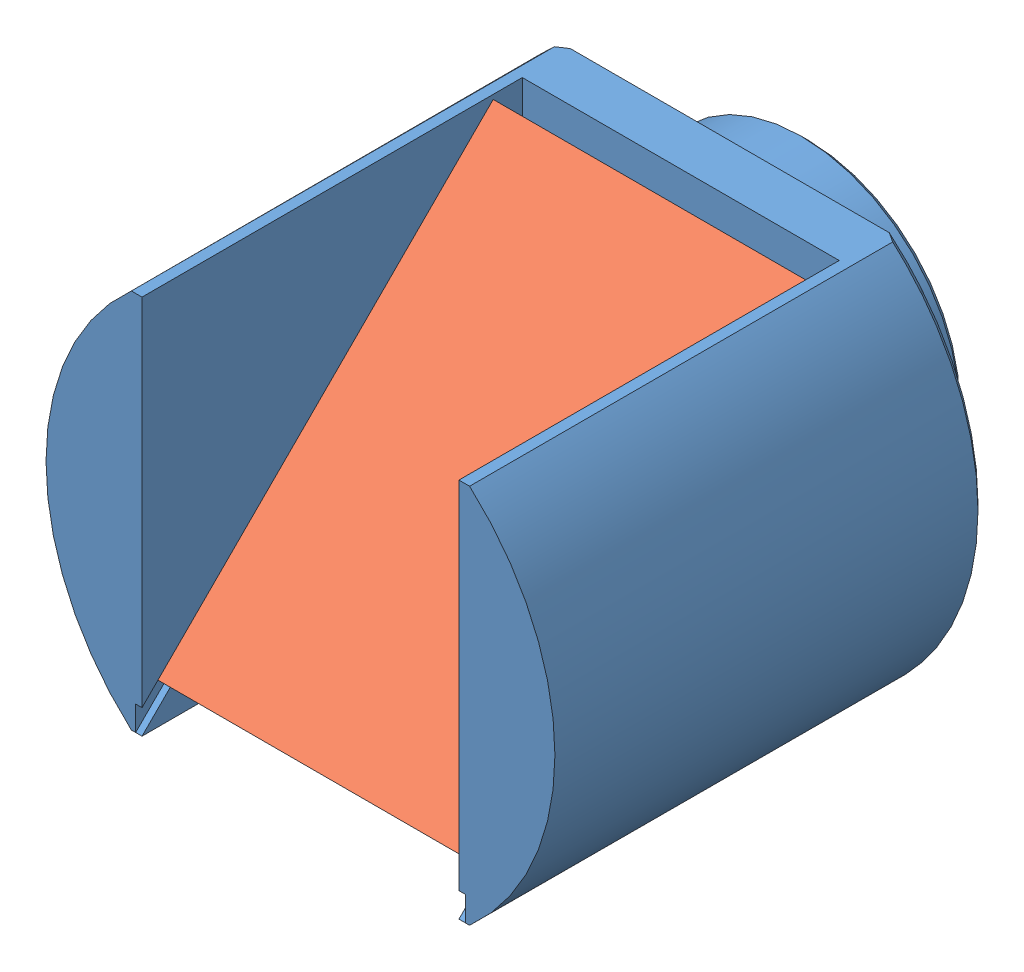
SolidWorks assembly LenseFixture4, configuration Default. Lengths in mm.
Overall size (40.79 30.48 40.64).
2 component instances, 2 part files, 3 mates.
Components (placement in the parent):
- Newport-UPA-CH1_5-1: Newport-UPA-CH1_5 [預設] at (-67.0687 16.6884 -1.5704) size (40.79 30.48 40.64)
- Lense1-1: Lense1 [Default] at (-65.4122 30.5849 9.9331) x (0 -0.707107 0.707107) z (0 0.707107 0.707107) size (38 26 1)
Mates (geometry in assembly coordinates):
- Coincident1: coincident: plane of Newport-UPA-CH1_5-1 through (-65.4122 29.3884 11.1296) normal (0 0.707107 0.707107); plane of Lense1-1 through (-65.4122 30.1234 10.3946) normal (0 -0.707107 -0.707107)
- Coincident2: coincident anti-aligned: plane of Lense1-1 through (-65.4122 30.8305 11.1017) normal (0 0.707107 -0.707107); plane of Newport-UPA-CH1_5-1 through (-65.4122 17.8849 -2.7669) normal (0 -0.707107 0.707107)
- Coincident3: coincident: plane of Newport-UPA-CH1_5-1 through (-65.4122 16.6884 -1.5704) normal (1 0 0); plane of Lense1-1 through (-65.4122 30.8305 11.1017) normal (-1 0 0)
